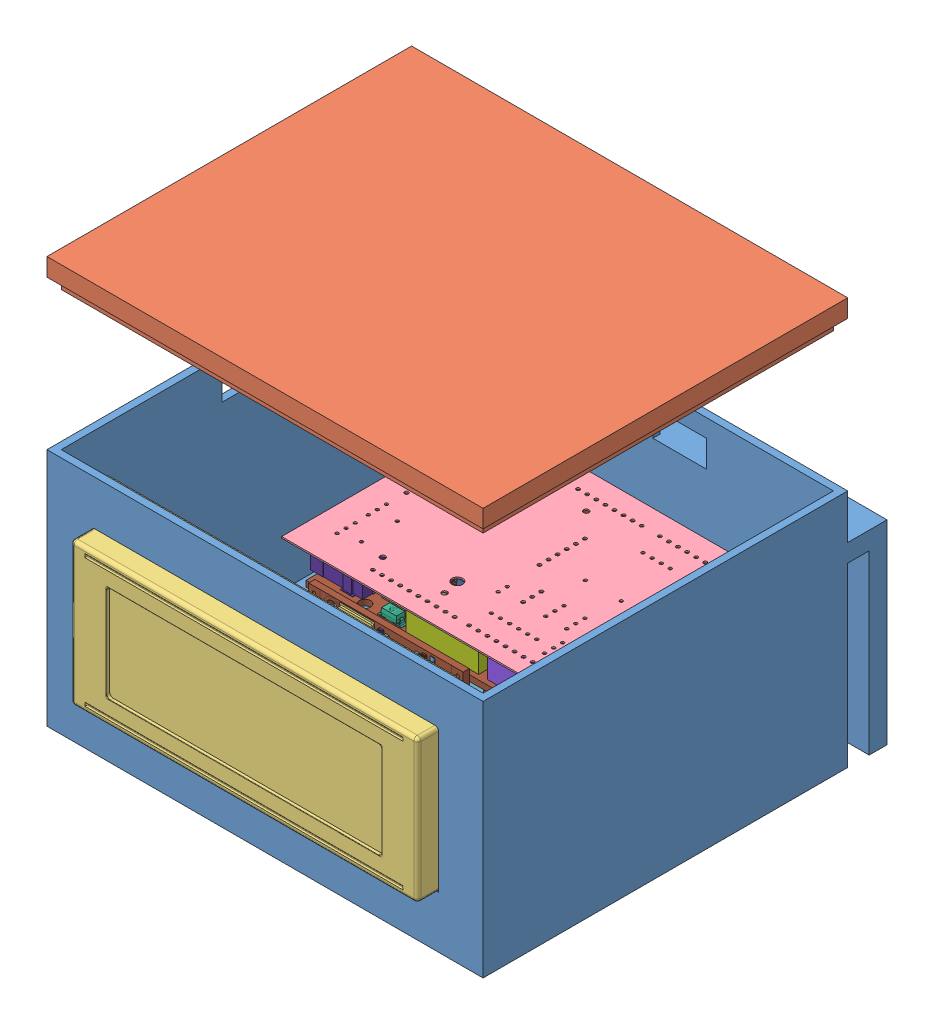
SolidWorks assembly Assem1, configuration Default. Lengths in mm.
Overall size (122 113.78 118.92).
132 component instances, 58 part files, 7 mates.
Components (placement in the parent):
- Top-1: Top [Default] at (35.1134 46.6104 110.7345) size (122 67 113)
- Bottom-1: Bottom [Default] at (35.1134 72.171 110.7345) size (122 8 102)
- LCD-1: LCD [По умолчанию] at (2.4237 108.6621 179.4345) x (1 0 0) z (0 -1 0) size (98 12.15 60)
- Relay - 4 Ch - 5v Montaj-1: Relay - 4 Ch - 5v Montaj [Varsayılan] at (45.8823 45.1479 44.0343) size (76 18.5 56)
  - 4 Ch - 5v Relay Board-1: 4 Ch - 5v Relay Board [Varsayılan] at (4.0193 3.4625 76) size (76 5.5 56)
  - Relay Body-1: Relay Body [Varsayılan] at (-20.4807 4.9625 77.25) size (15 18 19)
  - Relay Body-2: Relay Body [Varsayılan] at (-4.4807 4.9625 77.25) size (15 18 19)
  - Relay Body-3: Relay Body [Varsayılan] at (12.5193 4.9625 77.25) size (15 18 19)
  - Relay Body-4: Relay Body [Varsayılan] at (28.5193 4.9625 77.25) size (15 18 19)
  - Clamp Body-1: Clamp Body [Varsayılan] at (-20.4807 10.4625 90.75) x (-1 0 0) z (0 0 -1) size (15 10.5 8)
  - Metal Clamp Part-1: Metal Clamp Part [Varsayılan] at (-25.4807 8.4625 91.39) size (4 11.02 6)
  - Metal Clamp Part-2: Metal Clamp Part [Varsayılan] at (-20.4807 8.4625 91.39) size (4 11.02 6)
  - Metal Clamp Part-3: Metal Clamp Part [Varsayılan] at (-15.4807 8.4625 91.39) size (4 11.02 6)
  - Clamp Body-2: Clamp Body [Varsayılan] at (-4.4807 10.4625 90.75) x (-1 0 0) z (0 0 -1) size (15 10.5 8)
  - Clamp Body-4: Clamp Body [Varsayılan] at (12.5193 10.4625 90.75) x (-1 0 0) z (0 0 -1) size (15 10.5 8)
  - Clamp Body-5: Clamp Body [Varsayılan] at (28.5193 10.4625 90.75) x (-1 0 0) z (0 0 -1) size (15 10.5 8)
  - Metal Clamp Part-4: Metal Clamp Part [Varsayılan] at (-9.4807 8.4625 91.39) size (4 11.02 6)
  - Metal Clamp Part-5: Metal Clamp Part [Varsayılan] at (-4.4807 8.4625 91.39) size (4 11.02 6)
  - Metal Clamp Part-6: Metal Clamp Part [Varsayılan] at (0.5193 8.4625 91.39) size (4 11.02 6)
  - Metal Clamp Part-7: Metal Clamp Part [Varsayılan] at (7.5193 8.4625 91.39) size (4 11.02 6)
  - Metal Clamp Part-8: Metal Clamp Part [Varsayılan] at (12.5193 8.4625 91.39) size (4 11.02 6)
  - Metal Clamp Part-9: Metal Clamp Part [Varsayılan] at (17.5193 8.4625 91.39) size (4 11.02 6)
  - Metal Clamp Part-10: Metal Clamp Part [Varsayılan] at (23.5193 8.4625 91.39) size (4 11.02 6)
  - Metal Clamp Part-11: Metal Clamp Part [Varsayılan] at (28.5193 8.4625 91.39) size (4 11.02 6)
  - Metal Clamp Part-12: Metal Clamp Part [Varsayılan] at (33.5193 8.4625 91.39) size (4 11.02 6)
  - 6 Header-1: 6 Header [Varsayılan] at (-17.4807 4.9625 53) size (15 10.5 2.5)
  - 2 Header-1: 2 Header [Varsayılan] at (-30.9807 4.9625 62.5) x (0 0 -1) z (1 0 0) size (5 10.5 2.5)
  - Jumper-2: Jumper [Varsayılan] at (-30.9807 7.4625 62.5) x (0 0 -1) z (1 0 0) size (5 5.5 2.5)
- arduino uno-1: arduino uno [Default] at (14.4531 79.615 146.0493) x (0 0 1) z (-1 0 0) size (53.34 15.25 74.93)
  - unoboard blue-1: unoboard blue [Default] at origin size (53.34 1.65 68.58)
  - 47uf CAP Dcase-1: 47uf CAP Dcase [Default] at (-9.4141 0 -18.4991) x (0 0 -1) z (1 0 0) size (6.6 5.81 8)
  - USB type b-1: USB type b [Default] at (-38.02 0.43 6.35) size (14.34 15.2 16.5)
    - USB SHELL-1: USB SHELL [Default] at origin size (14.34 15.2 16.5)
    - USB core-1: USB core [Default] at origin size (11.3 10.68 15.75)
    - usb top contact-1: usb top contact [Default] at (1.25 6.09 -0.38) size (1 9.67 13.76)
    - usb btm contact-1: usb btm contact [Default] at (1.25 4.41 -0.38) size (1 6.84 11.76)
    - usb btm contact-2: usb btm contact [Default] at (-1.25 4.41 -0.38) size (1 6.84 11.76)
    - usb top contact-2: usb top contact [Default] at (-1.25 6.09 -0.38) size (1 9.67 13.76)
  - power jack-1: power jack [Default] at (-7.675 0 1.905) size (11.2 15.2 15.9)
  - 47uf CAP Dcase-2: 47uf CAP Dcase [Default] at (-9.4141 0 -25.7132) x (0 0 -1) z (1 0 0) size (6.6 5.81 8)
  - crystal-1: crystal [Default] at (-26.162 0 -18.923) x (1 0 0) z (0 0 -1) size (4 5 11)
  - 2pin_header__02-1: 2pin_header__02 [Default] at (-46.23 0 -15.75) size (5 11.75 2.54)
  - nano - reg-1: nano - reg [Default] at (-17.399 0 -7.747) size (6.5 1.69 8.3)
  - led-1: led [Default] at (-34.29 0 -27.94) x (0 0 1) z (-1 0 0) size (4 0.86 1.35)
  - 2pin_header__02-2: 2pin_header__02 [Default] at (-30.43 0 -64.91) x (0 0 1) z (-1 0 0) size (5 11.75 2.54)
  - dip28-1: dip28 [Default] at (-16.383 1.5 -46.355) x (0 0 -1) z (1 0 0) size (35.48 7.37 10.1)
    - dip28-1: dip28 [Default] at origin size (35.48 2.8 10.1)
    - dip socket pin-1: dip socket pin [Default] at (16.51 2.8 -3.81) size (1.7 7.37 1.7)
    - dip socket pin-2: dip socket pin [Default] at (16.51 2.8 3.81) size (1.7 7.37 1.7)
    - dip socket pin-3: dip socket pin [Default] at (13.97 2.8 -3.81) size (1.7 7.37 1.7)
    - dip socket pin-4: dip socket pin [Default] at (13.97 2.8 3.81) size (1.7 7.37 1.7)
    - dip socket pin-5: dip socket pin [Default] at (11.43 2.8 -3.81) size (1.7 7.37 1.7)
    - dip socket pin-6: dip socket pin [Default] at (11.43 2.8 3.81) size (1.7 7.37 1.7)
    - dip socket pin-7: dip socket pin [Default] at (8.89 2.8 -3.81) size (1.7 7.37 1.7)
    - dip socket pin-8: dip socket pin [Default] at (8.89 2.8 3.81) size (1.7 7.37 1.7)
    - dip socket pin-9: dip socket pin [Default] at (6.35 2.8 -3.81) size (1.7 7.37 1.7)
    - dip socket pin-10: dip socket pin [Default] at (6.35 2.8 3.81) size (1.7 7.37 1.7)
    - dip socket pin-11: dip socket pin [Default] at (3.81 2.8 -3.81) size (1.7 7.37 1.7)
    - dip socket pin-12: dip socket pin [Default] at (3.81 2.8 3.81) size (1.7 7.37 1.7)
    - dip socket pin-13: dip socket pin [Default] at (1.27 2.8 -3.81) size (1.7 7.37 1.7)
    - dip socket pin-14: dip socket pin [Default] at (1.27 2.8 3.81) size (1.7 7.37 1.7)
    - dip socket pin-15: dip socket pin [Default] at (-1.27 2.8 -3.81) size (1.7 7.37 1.7)
    - dip socket pin-16: dip socket pin [Default] at (-1.27 2.8 3.81) size (1.7 7.37 1.7)
    - dip socket pin-17: dip socket pin [Default] at (-3.81 2.8 -3.81) size (1.7 7.37 1.7)
    - dip socket pin-18: dip socket pin [Default] at (-3.81 2.8 3.81) size (1.7 7.37 1.7)
    - dip socket pin-19: dip socket pin [Default] at (-6.35 2.8 -3.81) size (1.7 7.37 1.7)
    - dip socket pin-20: dip socket pin [Default] at (-6.35 2.8 3.81) size (1.7 7.37 1.7)
    - dip socket pin-21: dip socket pin [Default] at (-8.89 2.8 -3.81) size (1.7 7.37 1.7)
    - dip socket pin-22: dip socket pin [Default] at (-8.89 2.8 3.81) size (1.7 7.37 1.7)
    - dip socket pin-23: dip socket pin [Default] at (-11.43 2.8 -3.81) size (1.7 7.37 1.7)
    - dip socket pin-24: dip socket pin [Default] at (-11.43 2.8 3.81) size (1.7 7.37 1.7)
    - dip socket pin-25: dip socket pin [Default] at (-13.97 2.8 -3.81) size (1.7 7.37 1.7)
    - dip socket pin-26: dip socket pin [Default] at (-13.97 2.8 3.81) size (1.7 7.37 1.7)
    - dip socket pin-27: dip socket pin [Default] at (-16.51 2.8 -3.81) size (1.7 7.37 1.7)
    - dip socket pin-28: dip socket pin [Default] at (-16.51 2.8 3.81) size (1.7 7.37 1.7)
  - 2pin_header__02-3: 2pin_header__02 [Default] at (-27.89 0 -64.91) x (0 0 1) z (-1 0 0) size (5 11.75 2.54)
  - 2pin_header__02-4: 2pin_header__02 [Default] at (-25.35 0 -64.91) x (0 0 1) z (-1 0 0) size (5 11.75 2.54)
  - 2pin_header__02-5: 2pin_header__02 [Default] at (-46.23 0 -18.29) size (5 11.75 2.54)
  - 2pin_header__02-6: 2pin_header__02 [Default] at (-46.23 0 -20.83) size (5 11.75 2.54)
  - atmega16u2-1: atmega16u2 [Default] at (-34.671 0.06 -20) x (1 0 0) z (0 0 -1) size (5.5 1.01 5.5)
  - led-2: led [Default] at (-36.83 0 -27.94) x (0 0 1) z (-1 0 0) size (4 0.86 1.35)
  - led-3: led [Default] at (-42.037 0 -27.94) x (0 0 1) z (-1 0 0) size (4 0.86 1.35)
  - led-4: led [Default] at (-36.576 0 -58.42) x (0 0 1) z (-1 0 0) size (4 0.86 1.35)
  - 8 PORT HEADER-3: 8 PORT HEADER [Default] at (-50.8 0 -45.72) x (0 0 -1) z (1 0 0) size (20.32 10.51 2.41)
  - 8 PORT HEADER-4: 8 PORT HEADER [Default] at (-2.54 0 -27.94) x (0 0 -1) z (1 0 0) size (20.32 10.51 2.41)
  - 6 PORT HEADER-3: 6 PORT HEADER [Default] at (-2.54 0 -50.8) x (0 0 -1) z (1 0 0) size (15.24 10.51 2.41)
  - 10 PORT HEADER-1: 10 PORT HEADER [Default] at (-50.8 0 -18.796) x (0 0 -1) z (1 0 0) size (25.4 10.51 2.41)
  - ATMEL328P-1: ATMEL328P [Default] at (-16.383 4.3 -46.355) x (0 0 -1) z (1 0 0) size (35 7.27 7.87)
  - 102 RESISTOR PACK-1: 102 RESISTOR PACK [Default] at (-33.782 0 -58.42) size (3.2 0.46 3)
  - 102 RESISTOR PACK-2: 102 RESISTOR PACK [Default] at (-39.37 0 -27.94) size (3.2 0.46 3)
  - 103 RESISTOR PACK-3: 103 RESISTOR PACK [Default] at (-23.876 0 -27.94) size (3.2 0.46 3)
  - 220 RESISTOR PACK-1: 220 RESISTOR PACK [Default] at (-36.83 0 -12.827) size (3.2 0.46 3)
  - 16mhz crystal - measured-1: 16mhz crystal - measured [Default] at (-24.892 0 -41.275) x (0 0 -1) z (1 0 0) size (3.4 0.8 2)
  - PADS001-1: PADS001 [Default] at (-39.878 0.1 -18.288) x (-1 0 0) z (0 0 1) size (4.54 0.1 4.54)
  - 603 cap on pad-1: 603 cap on pad [Default] at (-44.45 0 -27.94) x (0 0 -1) z (1 0 0) size (2.76 0.9 1.12)
  - ssot3-1: ssot3 [Default] at (-26.5 0 -8.128) x (-1 0 0) z (0 0 -1) size (3 1.13 3.09)
  - mf-msmf050-2-1: mf-msmf050-2 [Default] at (-26.5 0 -4.064) size (5.77 1.02 3.72)
  - 603 cap on pad-2: 603 cap on pad [Default] at (-29.845 0 -27.94) x (0 0 -1) z (1 0 0) size (2.76 0.9 1.12)
  - 603 cap on pad-3: 603 cap on pad [Default] at (-31.496 0 -27.94) x (0 0 -1) z (1 0 0) size (2.76 0.9 1.12)
  - lmv358-1: lmv358 [Default] at (-15.24 0 -21.971) x (0 0 -1) z (1 0 0) size (3.7 1.4 2.9)
  - 603 cap on pad-4: 603 cap on pad [Default] at (-15.24 0 -18.415) size (2.76 0.9 1.12)
  - 603 cap on pad-5: 603 cap on pad [Default] at (-29.845 0 -12.065) x (0 0 1) z (-1 0 0) size (2.76 0.9 1.12)
  - 603 cap on pad-6: 603 cap on pad [Default] at (-29.591 0 -22.352) x (0 0 1) z (-1 0 0) size (2.76 0.9 1.12)
  - 603 cap on pad-7: 603 cap on pad [Default] at (-29.591 0 -16.002) x (0 0 1) z (-1 0 0) size (2.76 0.9 1.12)
  - 603 cap on pad-8: 603 cap on pad [Default] at (-41.91 0 -12.7) x (0 0 1) z (-1 0 0) size (2.76 0.9 1.12)
  - lp2985dgkr-1: lp2985dgkr [Default] at (-20.32 0 -19.05) x (0 0 -1) z (1 0 0) size (5.85 1.1 3)
  - cd1206 diode-1: cd1206 diode [Default] at (-27.94 0 -59.436) x (0 0 -1) z (1 0 0) size (2.07 0.96 5)
  - cd1206 diode-2: cd1206 diode [Default] at (-46.228 0 -13.081) x (0 0 1) z (-1 0 0) size (2.07 0.96 5)
  - 603 resistor-1: 603 resistor [Default] at (-29.591 0 -19.05) x (0 0 1) z (-1 0 0) size (2.36 0.61 1.03)
  - blm21-1: blm21 [Default] at (-45.085 0 -7.62) x (0 0 -1) z (1 0 0) size (2.76 0.95 1.32)
  - m7 diode-1: m7 diode [Default] at (-2.794 0 -21.59) x (0 0 -1) z (1 0 0) size (6.66 2.35 2.5)
  - MLC0603-1: MLC0603 [Default] at (-33.655 0 -12.827) x (0 0 -1) z (1 0 0) size (2.36 0.6 1.03)
  - MLC0603-2: MLC0603 [Default] at (-39.37 0 -12.827) x (0 0 -1) z (1 0 0) size (2.36 0.6 1.03)
  - RESET BUTTON-1: RESET BUTTON [Default] at (-49.403 0 -6.35) size (6.2 3.1 9.6)
    - RESET CORE-1: RESET CORE [Default] at (0 0.1 0) x (-1 0 0) z (0 0 -1) size (6.2 3.1 9.6)
    - RESET-1: RESET [Default] at (0 0.1 0) x (0 0 1) z (-1 0 0) size (7.3 2 6.2)
  - 603 cap on pad-9: 603 cap on pad [Default] at (-15.24 0 -25.625) size (2.76 0.9 1.12)
- DS3231 RTC-1: DS3231 RTC [Default] at (88.8905 71.4596 129.5335) x (0 0 1) z (-1 0 0) size (44.75 22.8 13.53)
- converterLM2596-1: converterLM2596 [Default] at (41.0018 72.8911 148.4964) x (1 0 0) z (0 -1 0) size (43.2 15.15 21.25)
  - lm2596board-1: lm2596board [Default] at origin size (43.2 1.71 21.25)
  - smd100uF-1: smd100uF [Default] at (-17.25 2.55 0) x (0 0 -1) z (1 0 0) size (11.2 9.76 8.2)
  - smd220uF-2: smd220uF [Default] at (17.25 2.55 0) x (0 0 -1) z (1 0 0) size (11.2 9.76 8.2)
  - TrimmerW203-1: TrimmerW203 [Default] at (4.6271 6.95 -9.1276) size (9.5 15.15 4.81)
  - smdS537diode-1: smdS537diode [Default] at (-9.35 1.75 8.875) x (-1 0 0) z (0 0 -1) size (6.5 2.13 2.5)
  - smdceramiccapacitor-1: smdceramiccapacitor [Default] at (-15 1.7 5.7969) x (0 0 1) z (-1 0 0) size (2.55 0.62 1.3)
  - smdceramiccapacitor-2: smdceramiccapacitor [Default] at (-1.3196 1.7 -5.2916) x (0 0 1) z (-1 0 0) size (2.55 0.62 1.3)
  - smdResistor331-1: smdResistor331 [Default] at (-1.2696 1.7 -8.4665) x (0 0 1) z (-1 0 0) size (2.54 0.62 1.34)
  - smdResistor102-1: smdResistor102 [Default] at (10.7771 1.7 -8.4665) x (0 0 -1) z (1 0 0) size (2.54 0.62 1.34)
  - smdLED-1: smdLED [Default] at (13.0521 1.75 -8.4701) x (0 0 -1) z (1 0 0) size (3.2 0.84 1.28)
  - smbInductor470-1: smbInductor470 [Default] at (3.1271 2.1 3.175) size (12.5 7.41 12.5)
  - LM2596S-1: LM2596S [Default] at (-8.0627 1.8 -4.5407) size (9.8 4.61 14.95)
- PCB_T_Project_2_2023-06-21.step-1: PCB_T_Project_2_2023-06-21.step [Default] at (-18.6642 96.2613 62.1808) x (1 0 0) z (0 -1 0) size (71.63 58.8 0.41)
Mates (geometry in assembly coordinates):
- Coincident1: coincident anti-aligned: plane of Top-1 through (-6.9099 100.6104 174.621) normal (1 0 0); plane of LCD-1 through (-6.9099 101.1104 190.4845) normal (-1 0 0)
- Coincident2: coincident anti-aligned: plane of Top-1 through (-6.9099 61.1104 174.621) normal (0 1 0); plane of LCD-1 through (-6.9099 61.1104 190.4845) normal (0 -1 0)
- Coincident4: coincident anti-aligned: plane of Top-1 through (35.1134 48.6104 110.7345) normal (0 1 0); plane of Relay - 4 Ch - 5v Montaj-1/4 Ch - 5v Relay Board-1 through (14.9016 48.6104 145.0343) normal (0 -1 0)
- Parallel1: parallel anti-aligned: plane of arduino uno-1/unoboard blue-1 through (14.4531 77.965 146.0493) normal (0 0 1); plane of converterLM2596-1/lm2596board-1 through (41.0018 72.8911 148.4964) normal (0 0 -1)
- Parallel2: parallel aligned: plane of Top-1 through (35.1134 46.6104 110.7345) normal (0 -1 0); plane of arduino uno-1/unoboard blue-1 through (14.4531 77.965 146.0493) normal (0 -1 0)
- Parallel3: parallel anti-aligned: plane of arduino uno-1/unoboard blue-1 through (83.0331 77.965 140.9693) normal (1 0 0); plane of DS3231 RTC-1 through (88.8905 71.4596 129.5335) normal (-1 0 0)
- Parallel4: parallel anti-aligned: plane of Top-1 through (35.1134 48.6104 110.7345) normal (0 1 0); plane of PCB_T_Project_2_2023-06-21.step-1 through (53.3448 96.2613 126.5063) normal (0 -1 0)
